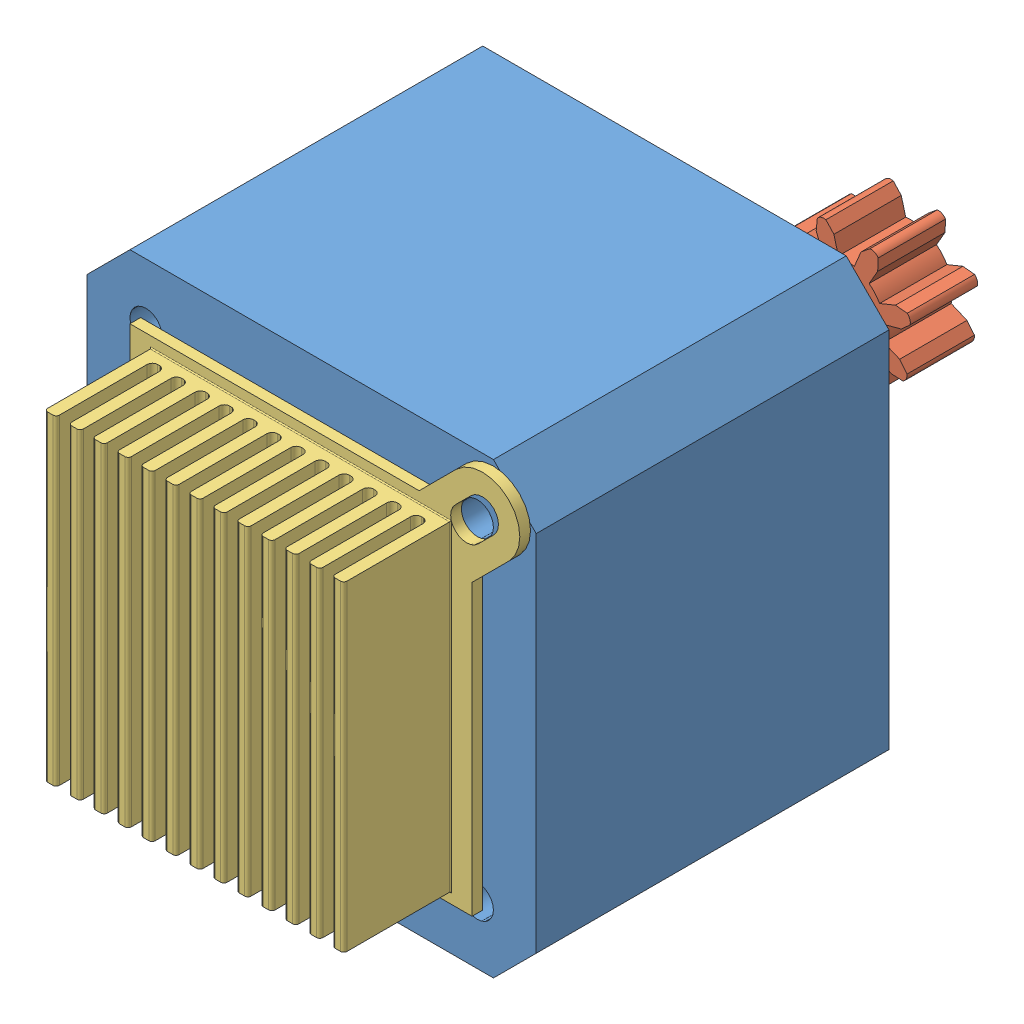
SolidWorks assembly 2.2 Silnik staw 0, configuration Domyślna. Lengths in mm.
Overall size (42 42 67.05).
3 component instances, 3 part files, 6 mates.
Components (placement in the parent):
- 2.2.1 Nema 17 x 33-1: 2.2.1 Nema 17 x 33 [Default] at origin size (42 42 56.05)
- 2.2.2 Small Gear-1: 2.2.2 Small Gear [Default] at (0 0 -23.05) x (-0.947695 -0.319178 0) z (0 0 1) size (13.1 13.1 6.3)
- 3.2.2 radiator-1: 3.2.2 radiator [Domyślna] at (-0.0002 -0.0002 33) x (0 1 0) z (1 0 0) size (40.94 11 40.94)
Mates (geometry in assembly coordinates):
- Koncentryczne6: concentric anti-aligned: cylinder of 2.2.1 Nema 17 x 33-1 through (0 0 -23.05) axis (0 0 1) radius 2.5; cylinder of 2.2.2 Small Gear-1 through (0 0 -16.75) axis (0 0 -1) radius 2.5
- Wspólnie1: coincident anti-aligned: plane of 2.2.1 Nema 17 x 33-1 through (0 0 33) normal (0 0 1); plane of 3.2.2 radiator-1 through (-0.0002 -0.0002 33) normal (0 0 -1)
- Koncentryczne7: concentric anti-aligned: cylinder of 2.2.1 Nema 17 x 33-1 through (15.5 15.5 33) axis (0 0 -1) radius 1.5; cylinder of 3.2.2 radiator-1 through (15.4996 15.4996 33) axis (0 0 1) radius 1.5
- Koncentryczne8: concentric anti-aligned: cylinder of 2.2.1 Nema 17 x 33-1 through (-15.5 -15.5 33) axis (0 0 -1) radius 1.5; cylinder of 3.2.2 radiator-1 through (-15.5 -15.5 33) axis (0 0 1) radius 1.5
- Wspólnie2: coordinate: point of 2.2.1 Nema 17 x 33-1; point of assembly
- Wspólnie3: coincident aligned: plane of 2.2.1 Nema 17 x 33-1 through (0 0 -23.05) normal (0 0 -1); plane of 2.2.2 Small Gear-1 through (0 0 -23.05) normal (0 0 -1)
